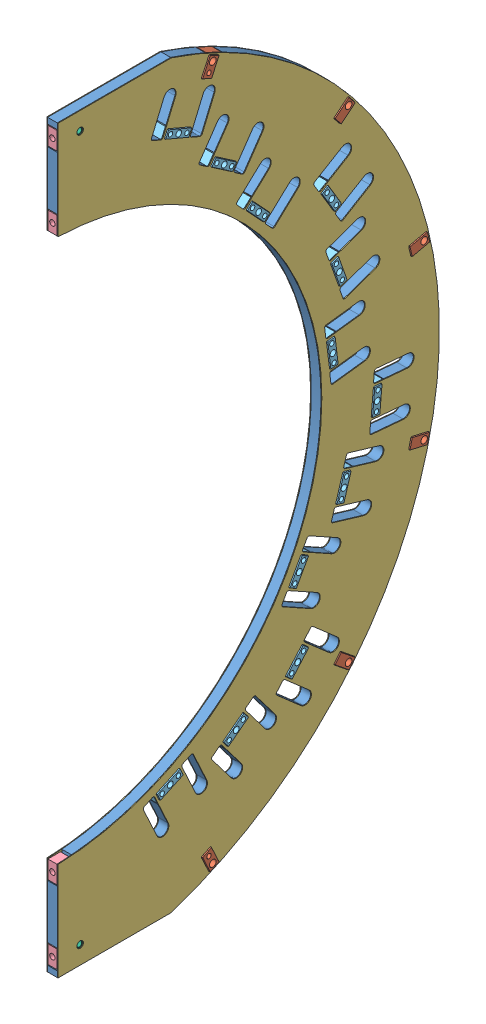
SolidWorks assembly Barrel 4 support panel assy, configuration left. Lengths in mm.
Overall size (6.75 413.5 213.1).
45 component instances, 7 part files, 56 mates.
Components (placement in the parent):
- Barrel 4 support panel core-2: Barrel 4 support panel core [left panel core] x (0 0 -1) z (1 0 0) size (213.1 413.5 5.43)
- Spaceframe disk mounting block-18: Spaceframe disk mounting block [without pin hole for barrel 4 support panel] at (0.505 133.1409 -164.4153) x (0 0.777146 0.62932) z (0 -0.62932 0.777146)
- Spaceframe disk mounting block-19: Spaceframe disk mounting block [without pin hole for barrel 4 support panel] at (0.505 47.5913 -206.1407) x (0 0.97437 0.224951) z (0 -0.224951 0.97437)
- Spaceframe disk mounting block-20: Spaceframe disk mounting block [without pin hole for barrel 4 support panel] at (0.505 -47.5913 -206.1407) x (0 0.97437 -0.224951) z (0 0.224951 0.97437)
- Spaceframe disk mounting block-21: Spaceframe disk mounting block [without pin hole for barrel 4 support panel] at (0.505 -133.1409 -164.4153) x (0 0.777146 -0.62932) z (0 0.62932 0.777146)
- Spaceframe disk mounting block-22: Spaceframe disk mounting block [Default for barrel 4 support panel] at (0.505 -191.7412 -89.4104) x (0 0.422618 -0.906308) z (0 0.906308 0.422618)
- Barrel 4 support skins-1: Barrel 4 support skins [Left panel skin 2] at (2.92 0 0) x (0 0 -1) z (1 0 0) size (213.1 413.5 0.41)
- Barrel 4 support skins-2: Barrel 4 support skins [Left panel skin 1] at (-2.92 0 0) x (0 0 -1) z (1 0 0) size (213.1 413.5 0.41)
- Barrel 1 support inserts-1: Barrel 1 support inserts [insert 2] at (0 -37 0) x (0 0 -1) z (-1 0 0)
- Barrel 1 support inserts-2: Barrel 1 support inserts [insert 2] at (0 4 0) x (0 0 -1) z (-1 0 0)
- Barrel 1 support inserts-3: Barrel 1 support inserts [insert 2] at (0 37 0) x (0 0 -1) z (1 0 0)
- Barrel 1 support inserts-4: Barrel 1 support inserts [insert 2] at (0 -4 0) x (0 0 -1) z (1 0 0)
- Spaceframe disk mounting block-1: Spaceframe disk mounting block [Default for barrel 4 support panel] at (0.505 191.7412 -89.4104) x (0 0.422618 0.906308) z (0 -0.906308 0.422618)
- Spaceframe disk mounting block-23: Spaceframe disk mounting block [without pin hole for barrel 4 support panel] at (-0.505 133.1409 -164.4153) x (0 -0.777146 -0.62932) z (0 -0.62932 0.777146) (suppressed, hidden)
- Spaceframe disk mounting block-24: Spaceframe disk mounting block [without pin hole for barrel 4 support panel] at (-0.505 47.5913 -206.1407) x (0 -0.97437 -0.224951) z (0 -0.224951 0.97437) (suppressed, hidden)
- Spaceframe disk mounting block-25: Spaceframe disk mounting block [without pin hole for barrel 4 support panel] at (-0.505 -47.5913 -206.1407) x (0 -0.97437 0.224951) z (0 0.224951 0.97437) (suppressed, hidden)
- Spaceframe disk mounting block-26: Spaceframe disk mounting block [without pin hole for barrel 4 support panel] at (-0.505 -133.1409 -164.4153) x (0 -0.777146 0.62932) z (0 0.62932 0.777146) (suppressed, hidden)
- Spaceframe disk mounting block-27: Spaceframe disk mounting block [Default for barrel 4 support panel] at (-0.505 -191.7412 -89.4104) x (0 -0.422618 0.906308) z (0 0.906308 0.422618) (suppressed, hidden)
- Barrel 3-4 support panel ladder mounting block-28: Barrel 3-4 support panel ladder mounting block [Default for barrel 4 support panel] at (-0.505 168.5725 -71.4448) x (0 -0.920721 0.390222) z (0 0.390222 0.920721) (suppressed, hidden)
- Barrel 3-4 support panel ladder mounting block-58: Barrel 3-4 support panel ladder mounting block [Default for barrel 4 support panel] at (-0.505 140.8138 -96.923) x (0 -0.823732 0.56698) z (0 0.56698 0.823732) (suppressed, hidden)
- Barrel 3-4 support panel ladder mounting block-62: Barrel 3-4 support panel ladder mounting block [Default for barrel 4 support panel] at (-0.505 108.3428 -116.112) x (0 -0.682223 0.731145) z (0 0.731145 0.682223) (suppressed, hidden)
- Barrel 3-4 support panel ladder mounting block-66: Barrel 3-4 support panel ladder mounting block [Default for barrel 4 support panel] at (0.505 168.5725 -71.4448) x (0 0.920721 -0.390222) z (0 0.390222 0.920721)
- Barrel 3-4 support panel ladder mounting block-76: Barrel 3-4 support panel ladder mounting block [Default for barrel 4 support panel] at (0.505 140.8138 -96.923) x (0 0.823732 -0.56698) z (0 0.56698 0.823732)
- Barrel 3-4 support panel ladder mounting block-80: Barrel 3-4 support panel ladder mounting block [Default for barrel 4 support panel] at (0.505 108.3428 -116.112) x (0 0.682223 -0.731145) z (0 0.731145 0.682223)
- Barrel 3-4 support panel ladder mounting block-63: Barrel 3-4 support panel ladder mounting block [Default for barrel 4 support panel] at (-0.505 19.2577 -157.6366) x (0 -0.121264 0.99262) z (0 0.99262 0.121264) (suppressed, hidden)
- Barrel 3-4 support panel ladder mounting block-64: Barrel 3-4 support panel ladder mounting block [Default for barrel 4 support panel] at (-0.505 -77.2039 -138.7793) x (0 0.486145 0.873878) z (0 0.873878 -0.486145) (suppressed, hidden)
- Barrel 3-4 support panel ladder mounting block-65: Barrel 3-4 support panel ladder mounting block [Default for barrel 4 support panel] at (-0.505 -144.093 -66.7635) x (0 0.907338 0.420402) z (0 0.420402 -0.907338) (suppressed, hidden)
- Barrel 3-4 support panel ladder mounting block-59: Barrel 3-4 support panel ladder mounting block [Default for barrel 4 support panel] at (-0.505 56.8031 -161.2328) x (0 -0.332286 0.943179) z (0 0.943179 0.332286) (suppressed, hidden)
- Barrel 3-4 support panel ladder mounting block-60: Barrel 3-4 support panel ladder mounting block [Default for barrel 4 support panel] at (-0.505 -48.9658 -163.7833) x (0 0.28644 0.958098) z (0 0.958098 -0.28644) (suppressed, hidden)
- Barrel 3-4 support panel ladder mounting block-61: Barrel 3-4 support panel ladder mounting block [Default for barrel 4 support panel] at (-0.505 -135.9786 -103.5975) x (0 0.795446 0.606024) z (0 0.606024 -0.795446) (suppressed, hidden)
- Barrel 3-4 support panel ladder mounting block-55: Barrel 3-4 support panel ladder mounting block [Default for barrel 4 support panel] at (-0.505 94.24 -156.9709) x (0 -0.514726 0.857355) z (0 0.857355 0.514726) (suppressed, hidden)
- Barrel 3-4 support panel ladder mounting block-56: Barrel 3-4 support panel ladder mounting block [Default for barrel 4 support panel] at (-0.505 -16.1906 -182.3702) x (0 0.088431 0.996082) z (0 0.996082 -0.088431) (suppressed, hidden)
- Barrel 3-4 support panel ladder mounting block-57: Barrel 3-4 support panel ladder mounting block [Default for barrel 4 support panel] at (-0.505 -120.4195 -137.9136) x (0 0.657716 0.753266) z (0 0.753266 -0.657716) (suppressed, hidden)
- Barrel 3-4 support panel ladder mounting block-81: Barrel 3-4 support panel ladder mounting block [Default for barrel 4 support panel] at (0.505 19.2577 -157.6366) x (0 0.121264 -0.99262) z (0 0.99262 0.121264)
- Barrel 3-4 support panel ladder mounting block-82: Barrel 3-4 support panel ladder mounting block [Default for barrel 4 support panel] at (0.505 -77.2039 -138.7793) x (0 -0.486145 -0.873878) z (0 0.873878 -0.486145)
- Barrel 3-4 support panel ladder mounting block-83: Barrel 3-4 support panel ladder mounting block [Default for barrel 4 support panel] at (0.505 -144.093 -66.7635) x (0 -0.907338 -0.420402) z (0 0.420402 -0.907338)
- Barrel 3-4 support panel ladder mounting block-77: Barrel 3-4 support panel ladder mounting block [Default for barrel 4 support panel] at (0.505 56.8031 -161.2328) x (0 0.332286 -0.943179) z (0 0.943179 0.332286)
- Barrel 3-4 support panel ladder mounting block-78: Barrel 3-4 support panel ladder mounting block [Default for barrel 4 support panel] at (0.505 -48.9658 -163.7833) x (0 -0.28644 -0.958098) z (0 0.958098 -0.28644)
- Barrel 3-4 support panel ladder mounting block-79: Barrel 3-4 support panel ladder mounting block [Default for barrel 4 support panel] at (0.505 -135.9786 -103.5975) x (0 -0.795446 -0.606024) z (0 0.606024 -0.795446)
- Barrel 3-4 support panel ladder mounting block-73: Barrel 3-4 support panel ladder mounting block [Default for barrel 4 support panel] at (0.505 94.24 -156.9709) x (0 0.514726 -0.857355) z (0 0.857355 0.514726)
- Barrel 3-4 support panel ladder mounting block-74: Barrel 3-4 support panel ladder mounting block [Default for barrel 4 support panel] at (0.505 -16.1906 -182.3702) x (0 -0.088431 -0.996082) z (0 0.996082 -0.088431)
- Barrel 3-4 support panel ladder mounting block-75: Barrel 3-4 support panel ladder mounting block [Default for barrel 4 support panel] at (0.505 -120.4195 -137.9136) x (0 -0.657716 -0.753266) z (0 0.753266 -0.657716)
- Adhesive-1: Adhesive [Default] at origin
- Barrel 4 support insert 3-1: Barrel 4 support insert 3 [Default] at (0 196.75 -16.8662)
- Barrel 4 support insert 3-2: Barrel 4 support insert 3 [Default] at (0 -196.75 -16.8662)
Mates (geometry in assembly coordinates):
- Coincident22: coincident anti-aligned: plane of Barrel 4 support panel core-2 through (0 0 0) normal (0 0 -1); plane of assembly through (0 0 0) normal (0 0 1)
- Coincident27: coincident aligned: plane of Barrel 4 support panel core-2; plane of assembly through (0 0 0) normal (0 1 0)
- Left Coincident70: coincident: plane of Spaceframe disk mounting block-1; line of assembly
- Left Angle11: planar angle = 0.436332 rad aligned: plane of assembly through (0 0 0) normal (0 0 1); plane of Spaceframe disk mounting block-1
- Left Distance14: distance = 214.063 mm: line of Spaceframe disk mounting block-1 through (9.8328 194.007 -90.4669) axis (-1 0 0); line of assembly
- Distance44: unknown = 0.1 mm anti-aligned: plane of Spaceframe disk mounting block-1 through (-2.615 186.0475 -89.7896) normal (-1 0 0); plane of Barrel 4 support skins-2 through (-2.715 0 0) normal (1 0 0)
- Coincident76: coincident aligned: plane of Barrel 4 support panel core-2 through (0 0 0) normal (1 0 0); plane of assembly through (0 0 0) normal (1 0 0)
- Coincident80: coincident aligned: plane of Barrel 4 support panel core-2 through (0 0 0) normal (1 0 0); plane of assembly through (0 0 0) normal (1 0 0)
- Coincident90: coincident aligned: plane of Barrel 4 support skins-1; plane of assembly through (0 0 0) normal (0 1 0)
- Coincident91: coincident aligned: plane of Barrel 4 support skins-2; plane of assembly through (0 0 0) normal (0 1 0)
- Coincident92: coincident anti-aligned: plane of Barrel 4 support skins-1 through (2.92 0 0) normal (0 0 -1); plane of assembly through (0 0 0) normal (0 0 1)
- Coincident93: coincident anti-aligned: plane of Barrel 4 support skins-2 through (-2.92 0 0) normal (0 0 -1); plane of assembly through (0 0 0) normal (0 0 1)
- Coincident94: coincident anti-aligned: plane of Barrel 4 support panel core-2 through (-2.715 0 0) normal (-1 0 0); plane of Barrel 4 support skins-2 through (-2.715 0 0) normal (1 0 0)
- Coincident95: coincident anti-aligned: plane of Barrel 4 support panel core-2 through (2.715 0 0) normal (1 0 0); plane of Barrel 4 support skins-1 through (2.715 0 0) normal (-1 0 0)
- Coincident96: coincident anti-aligned: plane of Barrel 1 support inserts-4 through (0 -4 0) normal (0 0 -1); plane of assembly through (0 0 0) normal (0 0 1)
- Coincident97: coincident anti-aligned: plane of Barrel 1 support inserts-3 through (0 37 0) normal (0 0 -1); plane of assembly through (0 0 0) normal (0 0 1)
- Coincident98: coincident anti-aligned: plane of Barrel 1 support inserts-2; plane of assembly through (0 0 0) normal (0 0 1)
- Coincident99: coincident anti-aligned: plane of Barrel 1 support inserts-1; plane of assembly through (0 0 0) normal (0 0 1)
- Coincident101: coincident anti-aligned: plane of Barrel 1 support inserts-1 through (0 -37 0) normal (-1 0 0); plane of assembly through (0 0 0) normal (1 0 0)
- Coincident102: coincident anti-aligned: plane of Barrel 1 support inserts-2 through (0 4 0) normal (-1 0 0); plane of assembly through (0 0 0) normal (1 0 0)
- Coincident103: coincident aligned: plane of Barrel 1 support inserts-3 through (0 37 0) normal (1 0 0); plane of assembly through (0 0 0) normal (1 0 0)
- Coincident104: coincident aligned: plane of Barrel 1 support inserts-4 through (0 -4 0) normal (1 0 0); plane of assembly through (0 0 0) normal (1 0 0)
- Distance1: unknown = 37 mm anti-aligned: line of Barrel 1 support inserts-1 through (-37 0 0) axis (-1 0 0); plane of assembly through (0 0 0) normal (0 1 0)
- Distance2: unknown = 4 mm anti-aligned: unknown of Barrel 1 support inserts-2; plane of assembly through (0 0 0) normal (0 1 0)
- Distance3: unknown = 37 mm aligned: unknown of Barrel 1 support inserts-3; plane of assembly through (0 0 0) normal (0 1 0)
- Distance4: unknown = 4 mm aligned: line of Barrel 1 support inserts-4 through (-2.7665 0 -4) axis (0 0 1); plane of assembly through (0 0 0) normal (0 1 0)
- Distance40: unknown = 0.1 mm anti-aligned: unknown of ?; plane of Barrel 4 support skins-1 through (2.715 0 0) normal (-1 0 0)
- right Angle1: unknown = 436.3323 mm: unknown of ?; plane of assembly through (0 0 0) normal (0 0 1)
- right Coincident107: coincident: unknown of ?
- right Distance5: unknown = 214.063 mm: line of ? through (-2.8708 209.2757 -42.5776) axis (1 0 0)
- Distance43: unknown = 0.1 mm anti-aligned: plane of ? through (3.225 128.4115 -75.4956) normal (-1 0 0); plane of Barrel 4 support skins-1 through (2.715 0 0) normal (-1 0 0)
- Coincident144: coincident: plane of ? through (-0.2313 135.1979 -70.0006) normal (0 0.459789 0.888028)
- Coincident161: coincident: point of Barrel 4 support panel core-2; line of Barrel 3-4 support panel ladder mounting block-28 through (4.0925 165.854 -68.7807) axis (-1 0 0)
- Distance42: unknown = 0.1 mm anti-aligned: plane of ? through (3.225 119.0681 -107.9927) normal (-1 0 0); plane of Barrel 4 support skins-1 through (2.715 0 0) normal (-1 0 0)
- Coincident147: coincident: plane of ? through (-0.2313 126.8473 -104.0263) normal (0 0.634121 0.773233)
- Coincident162: coincident: point of Barrel 4 support panel core-2; line of Barrel 3-4 support panel ladder mounting block-58 through (4.0925 139.78 -95.1898) axis (-1 0 0)
- Distance41: unknown = 0.1 mm anti-aligned: plane of ? through (3.225 103.4536 -138.023) normal (-1 0 0); plane of Barrel 4 support skins-1 through (2.715 0 0) normal (-1 0 0)
- Coincident150: coincident: plane of ? through (-0.2313 111.8524 -135.6334) normal (0 0.771499 0.63623)
- Coincident163: coincident: point of Barrel 4 support panel core-2; line of Barrel 3-4 support panel ladder mounting block-62 through (4.0925 108.7301 -115.5724) axis (-1 0 0)
- Distance47: unknown = 0.1 mm anti-aligned: plane of Barrel 3-4 support panel ladder mounting block-66 through (-2.615 169.4239 -64.2029) normal (-1 0 0); plane of Barrel 4 support skins-2 through (-2.715 0 0) normal (1 0 0)
- Coincident137: coincident: plane of Barrel 3-4 support panel ladder mounting block-66 through (0.505 168.5725 -71.4448) normal (0 0.390222 0.920721); line of assembly
- Coincident154: coincident: point of Barrel 4 support panel core-2; line of Barrel 3-4 support panel ladder mounting block-66 through (-2.927 168.5725 -71.4448) axis (1 0 0)
- Distance46: unknown = 0.1 mm anti-aligned: plane of Barrel 3-4 support panel ladder mounting block-76 through (-2.615 143.1006 -89.9991) normal (-1 0 0); plane of Barrel 4 support skins-2 through (-2.715 0 0) normal (1 0 0)
- Coincident139: coincident: plane of Barrel 3-4 support panel ladder mounting block-76 through (0.505 140.8138 -96.923) normal (0 0.56698 0.823732); line of assembly
- Distance45: unknown = 0.1 mm anti-aligned: plane of Barrel 3-4 support panel ladder mounting block-80 through (-2.615 112.0677 -109.8434) normal (-1 0 0); plane of Barrel 4 support skins-2 through (-2.715 0 0) normal (1 0 0)
- Coincident143: coincident: plane of Barrel 3-4 support panel ladder mounting block-80 through (0.505 108.3428 -116.112) normal (0 0.731145 0.682223); line of assembly
- Concentric16: concentric anti-aligned: cylinder of Barrel 4 support panel core-2 through (-5.285 196.75 -16.8662) axis (1 0 0) radius 4.5; cylinder of Barrel 4 support insert 3-1 through (2.515 196.75 -16.8662) axis (-1 0 0) radius 4
- Coincident151: coincident aligned: plane of Barrel 4 support insert 3-1 through (0 196.75 -16.8662) normal (1 0 0); plane of assembly through (0 0 0) normal (1 0 0)
- Parallel1: parallel aligned: plane of Barrel 4 support insert 3-1 through (0 196.75 -16.8662) normal (0 0 1); plane of assembly through (0 0 0) normal (0 0 1)
- Coincident153: coincident aligned: plane of Barrel 4 support insert 3-2 through (0 -196.75 -16.8662) normal (1 0 0); plane of assembly through (0 0 0) normal (1 0 0)
- Parallel2: parallel aligned: plane of Barrel 4 support insert 3-2 through (0 -196.75 -16.8662) normal (0 0 1); plane of assembly through (0 0 0) normal (0 0 1)
- Concentric17: concentric anti-aligned: cylinder of Barrel 4 support panel core-2 through (-5.285 -196.75 -16.8662) axis (1 0 0) radius 4.5; cylinder of Barrel 4 support insert 3-2 through (2.515 -196.75 -16.8662) axis (-1 0 0) radius 4
- Parallel4: parallel aligned: plane of Spaceframe disk mounting block-1; plane of Barrel 4 support skins-2 through (-2.715 194.7783 -94.1367) normal (0 0.422618 0.906308)
- Parallel5: parallel aligned: plane of Spaceframe disk mounting block-1 through (-2.615 188.3719 -84.8049) normal (0 0.422618 0.906308); plane of Barrel 4 support skins-1 through (3.125 194.7783 -94.1367) normal (0 0.422618 0.906308)
- Coincident158: coincident: point of Barrel 4 support panel core-2; line of Barrel 3-4 support panel ladder mounting block-76 through (-2.927 140.8138 -96.923) axis (1 0 0)
- Coincident160: coincident: unknown of Barrel 4 support panel core-2; line of Barrel 3-4 support panel ladder mounting block-80 through (-2.927 108.3428 -116.112) axis (1 0 0)
